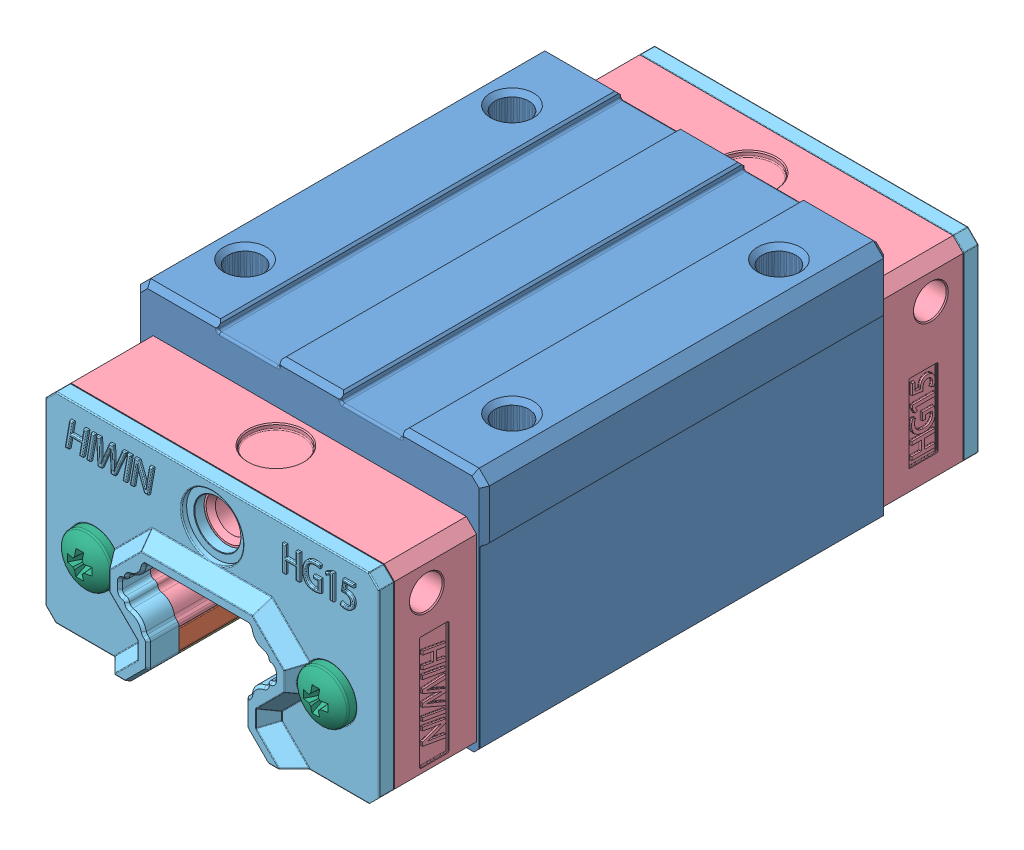
SolidWorks assembly HGH15CA, configuration Default. Lengths in mm.
Overall size (34 23.7 61.49).
11 component instances, 6 part files, 33 mates.
Components (placement in the parent):
- Copia de Copia de HGH15CA Block-1: Copia de Copia de HGH15CA Block [HGR15R300CE20] at origin size (34 23.7 39.4)
- Copia de Copia de HGx15CA Retainer-1: Copia de Copia de HGx15CA Retainer [HGR15R300CE20] at origin size (26 4 55.4)
- Copia de Copia de HGx15CA Tiny Red-1: Copia de Copia de HGx15CA Tiny Red [HGR15R300CE20] at origin size (14.2 1 55.4)
- Copia de Copia de HGx15CA End Cap-1: Copia de Copia de HGx15CA End Cap [HGR15R300CE20] at origin size (32.5 19.5 8)
- Copia de Copia de HGx15CA End Cap-2: Copia de Copia de HGx15CA End Cap [HGR15R300CE20] x (-1 0 0) z (0 0 -1) size (32.5 19.5 8)
- Copia de Copia de HGx15CA Seal-1: Copia de Copia de HGx15CA Seal [HGR15R300CE20] at origin size (32.5 19.5 3)
- Copia de Copia de HGx15CA Seal-2: Copia de Copia de HGx15CA Seal [HGR15R300CE20] x (-1 0 0) z (0 0 -1) size (32.5 19.5 3)
- pan head cross recess screw_iso-1: pan head cross recess screw_iso [ISO 7045 - M2.5 x 16 - Z - 16C] at (11.5 11.8 30.8) x (0 0 -1) z (0 -1 0) size (18.05 5 5)
- pan head cross recess screw_iso-2: pan head cross recess screw_iso [ISO 7045 - M2.5 x 16 - Z - 16C] at (-11.5 11.8 30.8) x (0 0 -1) z (0 1 0) size (18.05 5 5)
- pan head cross recess screw_iso-3: pan head cross recess screw_iso [ISO 7045 - M2.5 x 16 - Z - 16C] at (11.5 11.8 -30.8) x (0 0 1) z (0 -1 0) size (18.05 5 5)
- pan head cross recess screw_iso-4: pan head cross recess screw_iso [ISO 7045 - M2.5 x 16 - Z - 16C] at (-11.5 11.8 -30.8) x (0 0 1) z (0 1 0) size (18.05 5 5)
Mates (geometry in assembly coordinates):
- Coincident1: coincident aligned: plane of Copia de Copia de HGH15CA Block-1 through (0 0 0) normal (0 1 0); plane of Copia de Copia de HGx15CA Retainer-1 through (0 0 0) normal (0 1 0)
- Coincident2: coincident aligned: plane of Copia de Copia de HGH15CA Block-1 through (0 0 0) normal (0 0 1); plane of Copia de Copia de HGx15CA Retainer-1 through (0 0 0) normal (0 0 1)
- Coincident3: coincident aligned: plane of Copia de Copia de HGH15CA Block-1 through (0 0 0) normal (1 0 0); plane of Copia de Copia de HGx15CA Retainer-1 through (0 0 0) normal (1 0 0)
- Coincident4: coincident aligned: plane of Copia de Copia de HGH15CA Block-1 through (0 0 0) normal (0 1 0); plane of Copia de Copia de HGx15CA Tiny Red-1 through (0 0 0) normal (0 1 0)
- Coincident5: coincident aligned: plane of Copia de Copia de HGH15CA Block-1 through (0 0 0) normal (0 0 1); plane of Copia de Copia de HGx15CA Tiny Red-1 through (0 0 0) normal (0 0 1)
- Coincident6: coincident aligned: plane of Copia de Copia de HGH15CA Block-1 through (0 0 0) normal (1 0 0); plane of Copia de Copia de HGx15CA Tiny Red-1 through (0 0 0) normal (1 0 0)
- Coincident7: coincident aligned: plane of Copia de Copia de HGH15CA Block-1 through (0 0 0) normal (0 1 0); plane of Copia de Copia de HGx15CA End Cap-1 through (0 0 0) normal (0 1 0)
- Coincident8: coincident aligned: plane of Copia de Copia de HGH15CA Block-1 through (0 0 0) normal (0 0 1); plane of Copia de Copia de HGx15CA End Cap-1 through (0 0 0) normal (0 0 1)
- Coincident9: coincident aligned: plane of Copia de Copia de HGH15CA Block-1 through (0 0 0) normal (1 0 0); plane of Copia de Copia de HGx15CA End Cap-1 through (0 0 0) normal (1 0 0)
- Coincident10: coincident aligned: plane of Copia de Copia de HGH15CA Block-1 through (0 0 0) normal (0 1 0); plane of Copia de Copia de HGx15CA End Cap-2 through (0 0 0) normal (0 1 0)
- Coincident11: coincident anti-aligned: plane of Copia de Copia de HGH15CA Block-1 through (12.9 8.2 -19.7) normal (0 0 -1); plane of Copia de Copia de HGx15CA End Cap-2 through (-12.9 8.2 -19.7) normal (0 0 1)
- Coincident12: coincident anti-aligned: plane of Copia de Copia de HGH15CA Block-1 through (0 0 0) normal (1 0 0); plane of Copia de Copia de HGx15CA End Cap-2 through (0 0 0) normal (-1 0 0)
- Coincident14: coincident aligned: plane of Copia de Copia de HGH15CA Block-1 through (0 0 0) normal (0 1 0); plane of Copia de Copia de HGx15CA Seal-1 through (0 0 0) normal (0 1 0)
- Coincident15: coincident aligned: plane of Copia de Copia de HGH15CA Block-1 through (0 0 0) normal (0 0 1); plane of Copia de Copia de HGx15CA Seal-1 through (0 0 0) normal (0 0 1)
- Coincident16: coincident aligned: plane of Copia de Copia de HGH15CA Block-1 through (0 0 0) normal (1 0 0); plane of Copia de Copia de HGx15CA Seal-1 through (0 0 0) normal (1 0 0)
- Coincident17: coincident aligned: plane of Copia de Copia de HGH15CA Block-1 through (0 0 0) normal (0 1 0); plane of Copia de Copia de HGx15CA Seal-2 through (0 0 0) normal (0 1 0)
- Coincident18: coincident anti-aligned: plane of Copia de Copia de HGx15CA End Cap-2 through (-12.9 8.2 -27.7) normal (0 0 -1); plane of Copia de Copia de HGx15CA Seal-2 through (5.15 6.4157 -27.7) normal (0 0 1)
- Coincident19: coincident anti-aligned: plane of Copia de Copia de HGH15CA Block-1 through (0 0 0) normal (1 0 0); plane of Copia de Copia de HGx15CA Seal-2 through (0 0 0) normal (-1 0 0)
- Concentric1: concentric aligned: cylinder of Copia de Copia de HGx15CA Seal-1 through (11.5 11.8 28.7) axis (0 0 1) radius 1.5; cylinder of pan head cross recess screw_iso-1 through (11.5 11.8 56.2) axis (0 0 1) radius 1.25
- Concentric2: concentric aligned: cylinder of Copia de Copia de HGx15CA Seal-1 through (-11.5 11.8 28.7) axis (0 0 1) radius 1.5; cylinder of pan head cross recess screw_iso-2 through (-11.5 11.8 56.2) axis (0 0 1) radius 1.25
- Concentric3: concentric aligned: cylinder of Copia de Copia de HGx15CA Seal-2 through (11.5 11.8 -28.7) axis (0 0 -1) radius 1.5; cylinder of pan head cross recess screw_iso-3 through (11.5 11.8 -56.2) axis (0 0 -1) radius 1.25
- Concentric4: concentric aligned: cylinder of Copia de Copia de HGx15CA Seal-2 through (-11.5 11.8 -28.7) axis (0 0 -1) radius 1.5; cylinder of pan head cross recess screw_iso-4 through (-11.5 11.8 -56.2) axis (0 0 -1) radius 1.25
- Coincident20: coincident anti-aligned: plane of Copia de Copia de HGx15CA Seal-2 through (11.5 11.8 -28.7) normal (0 0 -1); plane of pan head cross recess screw_iso-3 through (10.25 11.8 -28.7) normal (0 0 1)
- Coincident21: coincident anti-aligned: plane of Copia de Copia de HGx15CA Seal-2 through (-11.5 11.8 -28.7) normal (0 0 -1); plane of pan head cross recess screw_iso-4 through (-10.25 11.8 -28.7) normal (0 0 1)
- Coincident22: coincident anti-aligned: plane of Copia de Copia de HGx15CA Seal-1 through (11.5 11.8 28.7) normal (0 0 1); plane of pan head cross recess screw_iso-1 through (12.75 11.8 28.7) normal (0 0 -1)
- Coincident23: coincident anti-aligned: plane of Copia de Copia de HGx15CA Seal-1 through (-11.5 11.8 28.7) normal (0 0 1); plane of pan head cross recess screw_iso-2 through (-12.75 11.8 28.7) normal (0 0 -1)
- Parallel1: parallel anti-aligned: plane of Copia de Copia de HGH15CA Block-1 through (0 0 0) normal (0 1 0); plane of pan head cross recess screw_iso-1 through (11.5 11.8 30.8) normal (0 -1 0)
- Parallel2: parallel aligned: plane of Copia de Copia de HGH15CA Block-1 through (0 0 0) normal (0 1 0); plane of pan head cross recess screw_iso-2 through (-11.5 11.8 30.8) normal (0 1 0)
- Parallel3: parallel anti-aligned: plane of Copia de Copia de HGH15CA Block-1 through (0 0 0) normal (0 1 0); plane of pan head cross recess screw_iso-3 through (11.5 11.8 -30.8) normal (0 -1 0)
- Parallel4: parallel aligned: plane of Copia de Copia de HGH15CA Block-1 through (0 0 0) normal (0 1 0); plane of pan head cross recess screw_iso-4 through (-11.5 11.8 -30.8) normal (0 1 0)
- Concentric5: concentric anti-aligned: cylinder of Copia de Copia de HGx15CA Seal-1 through (0 20.05 28.7) axis (0 0 1) radius 2.25; cylinder of ? through (0 20.05 33.5) axis (0 0 -1) radius 2
- Coincident24: coincident anti-aligned: plane of Copia de Copia de HGx15CA Seal-1 through (0 20.05 28.7) normal (0 0 1); plane of ? through (-2.75 20.05 28.7) normal (0 0 -1)
- Parallel6: parallel aligned: plane of Copia de Copia de HGH15CA Block-1 through (0 0 0) normal (0 1 0); plane of ? through (0 20.05 39.2) normal (0 1 0)
